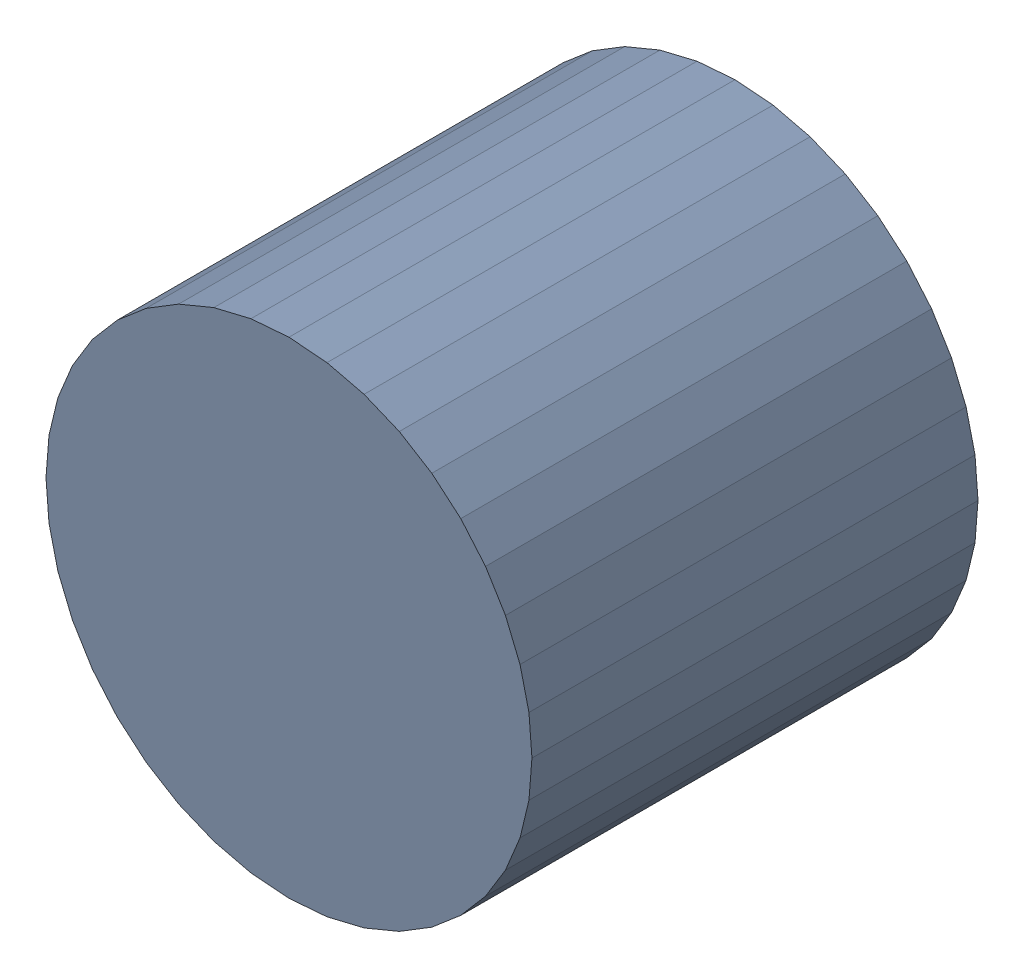
SolidWorks assembly C10_Motor_2Kanaloa_v2.0.0_Motor, configuration Default. Lengths in mm.
Overall size (6.32 6.32 5.8).
2 component instances, 1 part files, 0 mates.
Components (placement in the parent):
- 352892112-1: 352892112 [Default] at (131.508 44.45 0) size (6.32 6.32 5.8)
  - Extruded_11-1: Extruded_11 [Default] at origin size (6.32 6.32 5.8)
